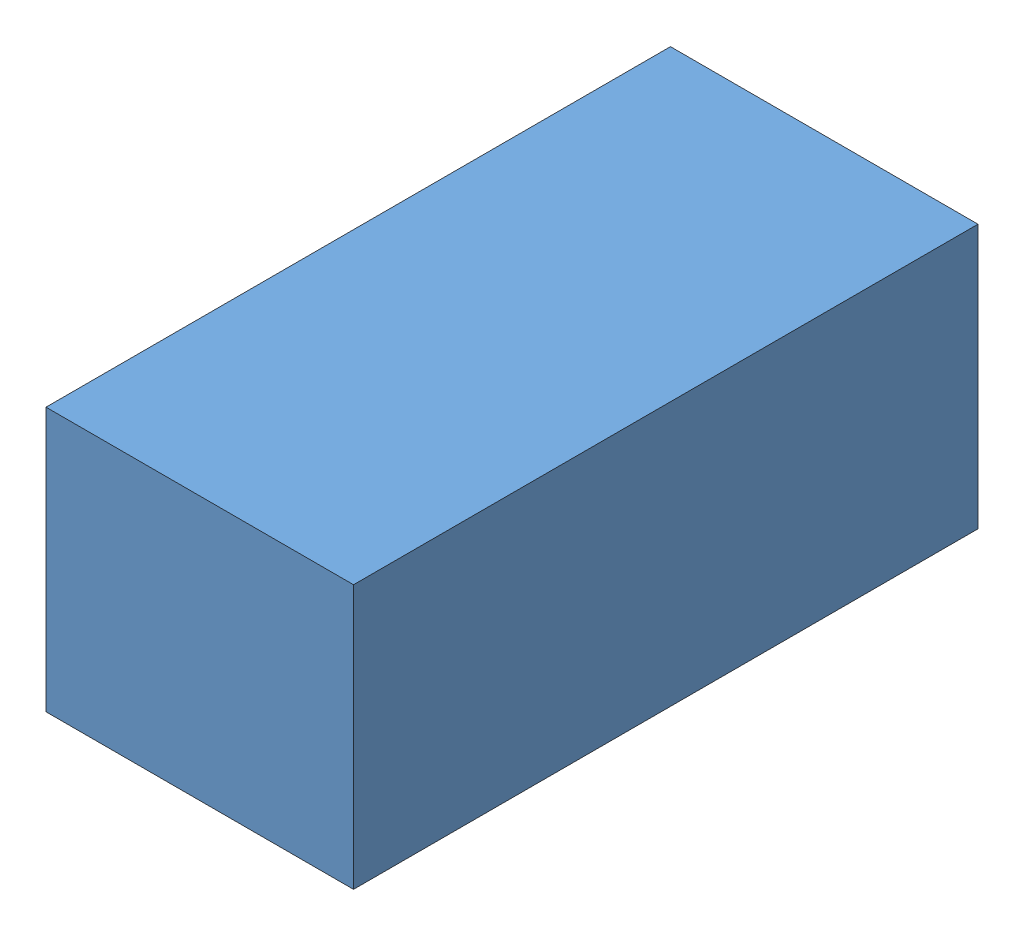
SolidWorks assembly Ensamblaje1, configuration Predeterminado. Lengths in mm.
Overall size (1185 945 2400).
2 component instances, 2 part files, 3 mates.
Components (placement in the parent):
- tablero de baja 3200 amp-1: tablero de baja 3200 amp [Predeterminado] at (199.3445 -1886.3674 -1010.0889) size (1185 945 2400)
- pantalla de baja-1: pantalla de baja [Predeterminado] at (199.3445 -2243.8674 298.6611) x (1 0 0) z (0 -1 0) size (223 141 124.6)
Mates (geometry in assembly coordinates):
- Coincidente1: coincident anti-aligned: plane of tablero de baja 3200 amp-1 through (-215.1555 -2243.8674 987.9111) normal (0 -1 0); plane of pantalla de baja-1 through (97.8445 -2243.8674 238.1611) normal (0 1 0)
- Ancho1: width aligned: plane of tablero de baja 3200 amp-1 through (279.3445 -2241.8674 245.4111) normal (-1 0 0); plane of tablero de baja 3200 amp-1 through (119.3445 -2241.8674 362.9111) normal (1 0 0); plane of pantalla de baja-1 through (119.5945 -2134.2674 245.4111) normal (-1 0 0); plane of pantalla de baja-1 through (279.0945 -2134.2674 245.4111) normal (1 0 0)
- Coincidente2: coincident anti-aligned: plane of tablero de baja 3200 amp-1 through (119.3445 -2241.8674 245.4111) normal (0 0 1); plane of pantalla de baja-1 through (279.0945 -2134.2674 245.4111) normal (0 0 -1)
